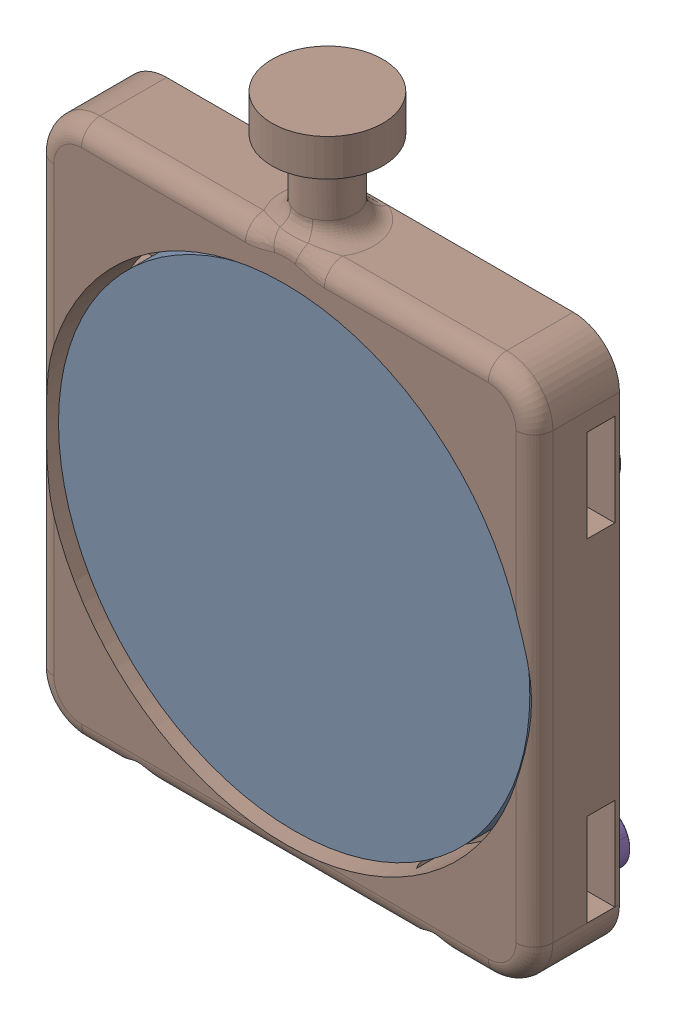
SolidWorks assembly assembly_polarizer_openSIM_V2.0, configuration Default. Lengths in mm.
Overall size (27.17 35 6.2).
8 component instances, 3 part files, 0 mates.
Components (placement in the parent):
- polarizer_openSIM_V2.0-1: polarizer_openSIM_V2.0 [Default] at (13.5 -19.3593 0.1635) size (25.5 25.5 2.5)
- HXN3_1_openSIM_V2.0-8: HXN3_1_openSIM_V2.0 [Default] at (21.4791 -30.8593 -0.21) x (0 -1 0) z (0 0 1) size (1 3 3)
- HXN3_1_openSIM_V2.0-14: HXN3_1_openSIM_V2.0 [Default] at (5.3844 -31.8593 -0.2374) x (0 1 0) z (0 0 1) size (1 3 3)
- HXN3_1_openSIM_V2.0-19: HXN3_1_openSIM_V2.0 [Default] at (24.7181 -11.0746 -2.3365) x (0 0 1) z (-1 0 0) size (1 3 3)
- HXN3_1_openSIM_V2.0-20: HXN3_1_openSIM_V2.0 [Default] at (25.2067 -28.8439 -1.3365) x (0 0 -1) z (0.923728 0.383049 0) size (1 3 3)
- HXN3_1_openSIM_V2.0-22: HXN3_1_openSIM_V2.0 [Default] at (1.7014 -28.6958 -2.3365) x (0 0 1) z (-1 0 0) size (1 3 3)
- HXN3_1_openSIM_V2.0-23: HXN3_1_openSIM_V2.0 [Default] at (2.2137 -10.8965 -2.3365) x (0 0 1) z (-1 0 0) size (1 3 3)
- polarizer_holder_openSIM_V2.0-2: polarizer_holder_openSIM_V2.0 [Default] at (0 -33.3593 -1.4365) size (27 35 6)
